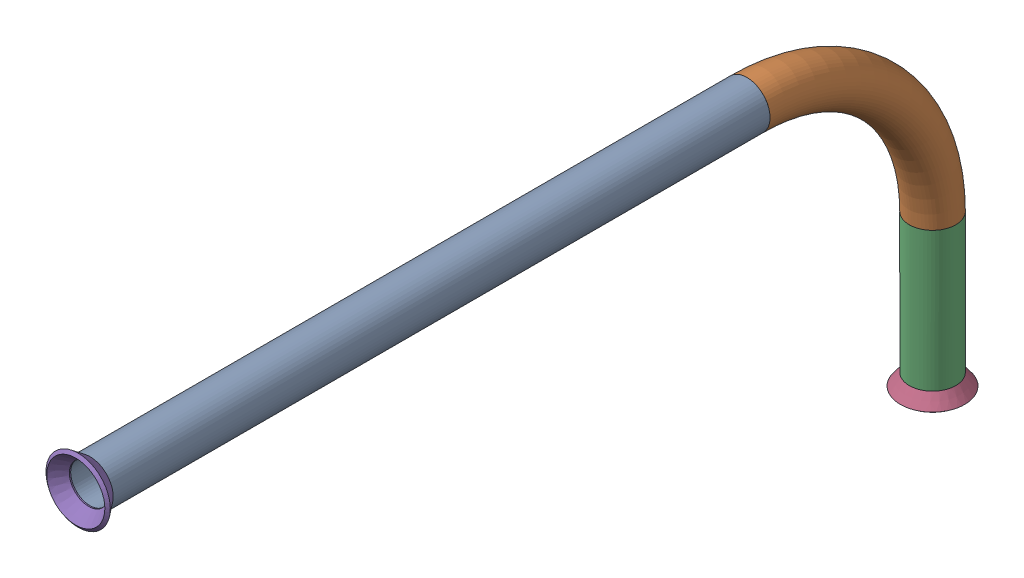
SolidWorks assembly Pipe 48, configuration Default. Lengths in mm.
Overall size (17.59 101.58 243.16).
3 component instances, 2 part files, 3 mates.
Components (placement in the parent):
- Part5-1: Part5 [Default<As Machined>] at origin size (12.7 95.25 236.83)
- Flared pipe end - .5 inch-1: Flared pipe end - .5 inch [Default<As Machined>] at (0 -321.7178 78.8392) x (-1 0 0) z (0 -1 0) size (17.59 17.59 3.89)
- Flared pipe end - .5 inch-2: Flared pipe end - .5 inch [Default<As Machined>] at (0 -232.8178 309.3187) size (17.59 17.59 3.89)
Mates (geometry in assembly coordinates):
- Concentric846: concentric: circle of Part5-1; circle of Flared pipe end - .5 inch-1
- Coincident1639: coincident: plane of Part5-1 through (0 -321.7178 78.8392) normal (0 -1 0); plane of Flared pipe end - .5 inch-1 through (0 -321.7178 73.556) normal (0 1 0)
- Coincident1638: coincident: circle of Part5-1; circle of Flared pipe end - .5 inch-2
